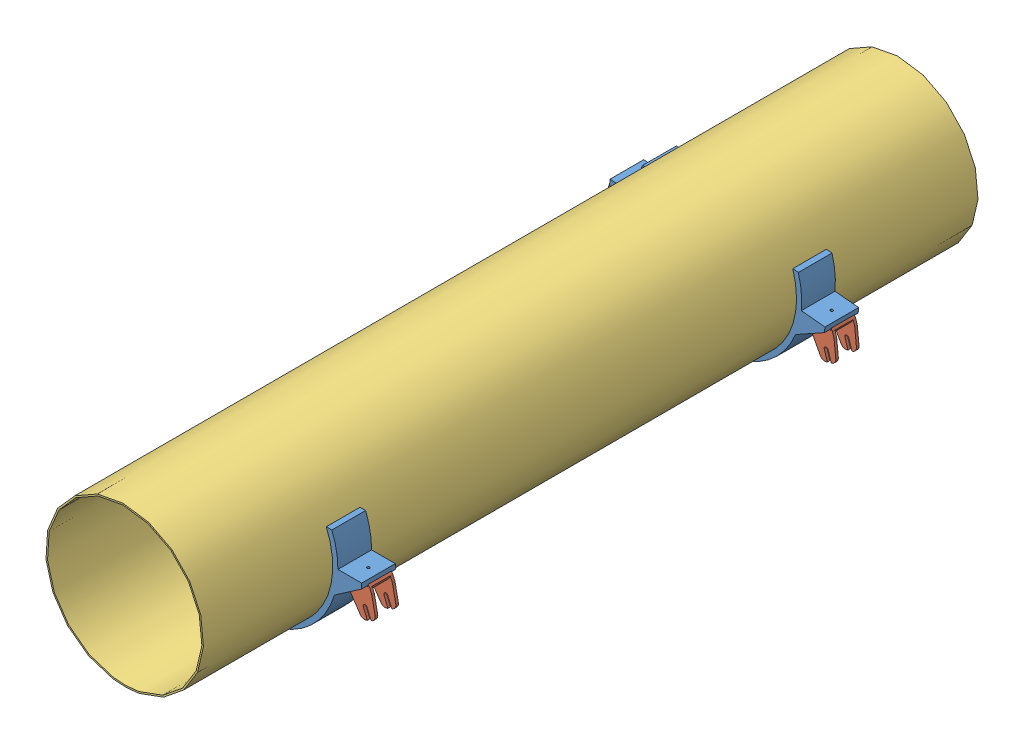
SolidWorks assembly Ensamblaje3, configuration Predeterminado. Lengths in mm.
Overall size (489.22 360.61 1500).
11 component instances, 3 part files, 2 mates.
Components (placement in the parent):
- Circulo completo-1: Circulo completo [Predeterminado] at (-50.2331 -13.1766 468.1075) size (468.11 243.35 65.25)
  - Medio circulo-1: Medio circulo [Predeterminado] at (-194.9548 72.1041 243.3498) size (209 243.35 65.25)
  - Medio circulo-2: Medio circulo [Predeterminado] at (-194.9548 72.1041 308.5998) x (-1 0 0) z (0 0 -1) size (209 243.35 65.25)
  - Base Basculante-1: Base Basculante [Predeterminado] at (23.6058 44.0052 253.5998) x (0.923077 0.384615 0) z (0 0 1) size (46 70 45)
  - Base Basculante-2: Base Basculante [Predeterminado] at (-413.3425 44.0052 298.6493) x (-0.92306 0.384615 0.005562) z (-0.006025 0 -0.999982) size (46 70 45)
- Circulo completo-2: Circulo completo [Predeterminado] at (-58.0177 -31.4809 -430.0272) x (0.995421 -0.095583 0) z (0 0 1) size (468.11 243.35 65.25)
  - Medio circulo-1: Medio circulo [Predeterminado] at (-194.9548 72.1041 243.3498) size (209 243.35 65.25)
  - Medio circulo-2: Medio circulo [Predeterminado] at (-194.9548 72.1041 308.5998) x (-1 0 0) z (0 0 -1) size (209 243.35 65.25)
  - Base Basculante-1: Base Basculante [Predeterminado] at (23.6058 44.0052 253.5998) x (0.923077 0.384615 0) z (0 0 1) size (46 70 45)
  - Base Basculante-2: Base Basculante [Predeterminado] at (-413.3425 44.0052 298.6493) x (-0.92306 0.384615 0.005562) z (-0.006025 0 -0.999982) size (46 70 45)
- Cilindro acrilico-1: Cilindro acrilico [Predeterminado] at (-245.1879 58.9275 -473.1839) x (0.999793 0.020362 0) z (0.020362 -0.999793 0) size (306 1500 306)
Mates (geometry in assembly coordinates):
- Concéntrica2: concentric anti-aligned: cylinder of Circulo completo-2/Medio circulo-2 through (-245.1879 58.9275 -186.6774) axis (0 0 1) radius 153; cylinder of Cilindro acrilico-1 through (-245.1879 58.9275 1026.8161) axis (0 0 -1) radius 153
- Concéntrica3: concentric anti-aligned: cylinder of Circulo completo-1/Medio circulo-2 through (-245.1879 58.9275 711.4573) axis (0 0 1) radius 153; cylinder of Cilindro acrilico-1 through (-245.1879 58.9275 1026.8161) axis (0 0 -1) radius 153
